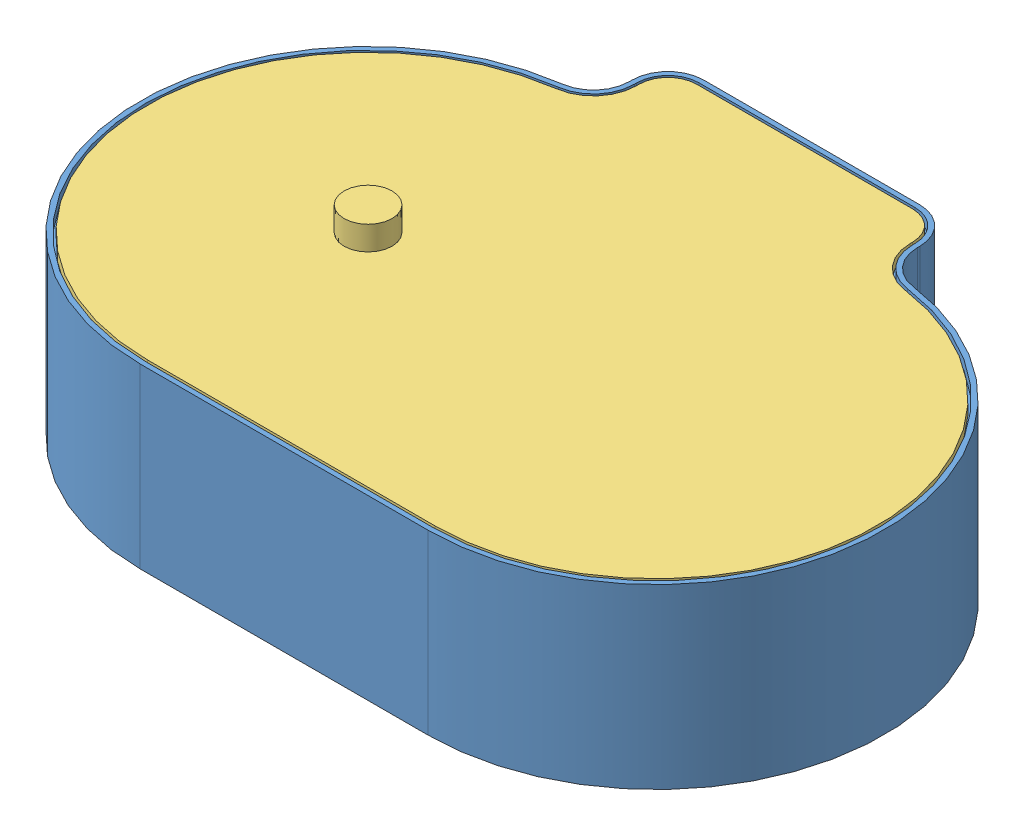
SolidWorks assembly Assem1, configuration Default. Lengths in mm.
Overall size (155 52 110).
3 component instances, 3 part files, 6 mates.
Components (placement in the parent):
- base-1: base [Default] at (2.9706 -32.4518 15.4111) size (155 37 110)
- botton-1: botton [Default] at (13.9706 -20.4518 -16.5889) x (1 0 0) z (0 -1 0) size (55 68 24)
- tampa-1: tampa [Default] at (2.9706 2.5482 15.4111) x (1 0 0) z (0 1 0) size (152 107 12)
Mates (geometry in assembly coordinates):
- Concentric2: concentric anti-aligned: cylinder of base-1 through (32.9706 -30.4518 15.4111) axis (0 -1 0) radius 32.5; cylinder of botton-1 through (32.9706 -42.4518 15.4111) axis (0 1 0) radius 32
- Parallel3: parallel anti-aligned: plane of base-1 through (12.9706 -30.4518 -17.0889) normal (1 0 0); plane of botton-1 through (13.9706 -42.4518 -16.5889) normal (-1 0 0)
- Coincident5: coincident: plane of base-1 through (32.9706 -20.4518 15.4111) normal (0 1 0); plane of botton-1 through (32.9706 -20.4518 15.4111) normal (0 1 0)
- Coincident6: coincident anti-aligned: plane of base-1 through (32.9706 2.5482 15.4111) normal (0 1 0); plane of tampa-1 through (40.4706 2.5482 -39.0751) normal (0 -1 0)
- Distance2: distance = 0.5 mm anti-aligned: plane of tampa-1 through (25.4706 4.5482 -45.5889) normal (0 0 -1); plane of base-1 through (25.4706 4.5482 -46.0889) normal (0 0 1)
- Distance3: distance = 0.5 mm anti-aligned: plane of base-1 through (-26.0294 4.5482 -39.5889) normal (1 0 0); plane of tampa-1 through (-25.5294 4.5482 -39.5889) normal (-1 0 0)
